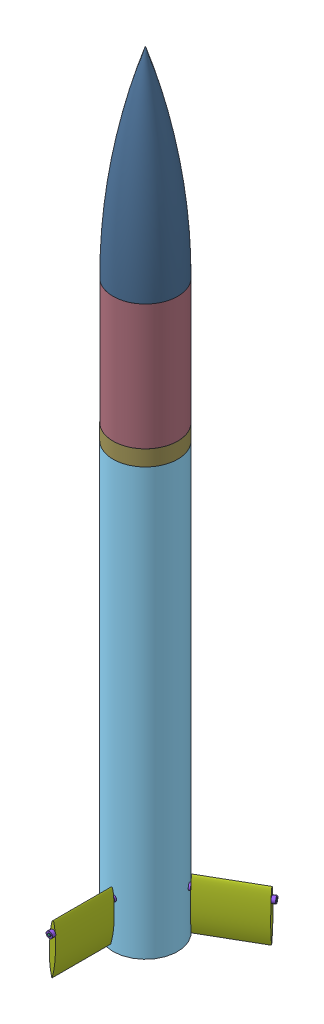
SolidWorks assembly Rocket flow study, configuration Default. Lengths in mm.
Overall size (346.59 1555.75 300.71).
35 component instances, 14 part files, 41 mates.
Components (placement in the parent):
- 57155K324_STAINLESS STEEL BALL BEARING-1: 57155K324_STAINLESS STEEL BALL BEARING [57155K324] at (60.6025 59.8698 -15.8313) x (-0.999722 -0.023582 0) z (0 0 1) size (17.53 17.53 4.98)
- 57155K324_STAINLESS STEEL BALL BEARING-2: 57155K324_STAINLESS STEEL BALL BEARING [57155K324] at (60.6025 59.8698 -3.5377) x (0.802682 0.596408 0) z (0 0 -1) size (17.53 17.53 4.98)
- three_fin_design-1: three_fin_design [Default] at (60.6025 -34.1102 -62.5321) size (127 120.65 127)
- Servo model-1: Servo model [Default] at (8.2588 8.1198 -93.0933) x (0.866025 0 0.5) z (0.5 0 -0.866025) size (29.41 54 21)
- 57155K324_STAINLESS STEEL BALL BEARING-3: 57155K324_STAINLESS STEEL BALL BEARING [57155K324] at (9.5118 59.8698 -92.0293) x (0.5 0 -0.866025) z (0.866025 0 0.5) size (17.53 17.53 4.98)
- 57155K324_STAINLESS STEEL BALL BEARING-4: 57155K324_STAINLESS STEEL BALL BEARING [57155K324] at (20.1584 59.8698 -85.8825) x (-0.5 0 0.866025) z (-0.866025 0 -0.5) size (17.53 17.53 4.98)
- 57155K324_STAINLESS STEEL BALL BEARING-5: 57155K324_STAINLESS STEEL BALL BEARING [57155K324] at (101.0466 59.8698 -85.8825) x (-0.5 0 -0.866025) z (0.866025 0 -0.5) size (17.53 17.53 4.98)
- 57155K324_STAINLESS STEEL BALL BEARING-7: 57155K324_STAINLESS STEEL BALL BEARING [57155K324] at (111.6932 59.8698 -92.0293) x (0.292704 -0.810739 0.506978) z (-0.866025 0 0.5) size (17.53 17.53 4.98)
- motor tube-2: motor tube [Default] at (60.6025 -34.1102 -62.5321) x (0.500398 0 0.865795) z (-0.865795 0 0.500398) size (58 240 58)
- Servo model-2: Servo model [Default] at (60.3075 8.1198 -1.9205) x (0 0 -1) z (-1 0 0) size (29.41 54 21)
- Servo model-3: Servo model [Default] at (113.2412 8.1198 -92.5824) x (-0.866025 0 0.5) z (0.5 0 0.866025) size (29.41 54 21)
- BodyTube(34in)-1: BodyTube(34in) [Default] at (60.6025 -34.1102 -62.5321) x (-0.070711 0 0.997497) z (-0.997497 0 -0.070711) size (130.89 863.6 130.89)
- fin_assembly-1: fin_assembly [Default] at (-45.0569 295.68 404.8684) x (0.011108 -0.999753 0.01924) z (0.866025 0 -0.5) size (102.27 14.01 158.75)
  - 8632T141_D-PROFILE SHAFT-1: 8632T141_D-PROFILE SHAFT [8632T141] at (227.9327 357.1031 441.2341) size (6.35 5.92 158.75)
  - fin-1: fin [Default] at (206.3327 357.1031 393.8313) size (102.27 12.29 119)
  - 9414T600_SET SCREW SHAFT COLLAR-1: 9414T600_SET SCREW SHAFT COLLAR [9414T6] at (227.9327 357.1031 516.4022) x (-0.10942 -0.993996 0) z (0 0 1) size (12.7 12.7 7.14)
  - 9414T600_SET SCREW SHAFT COLLAR-2: 9414T600_SET SCREW SHAFT COLLAR [9414T6] at (227.9327 357.1031 390.2594) x (-0.10942 -0.993996 0) z (0 0 1) size (12.7 12.7 7.14)
- horn-1: horn [Default] at (86.048 -3.2802 -76.8824) x (0.499417 0.048297 0.865015) z (-0.024148 0.998833 -0.041826) size (44 6 12)
- horn-2: horn [Default] at (60.3075 -3.2802 -33.3205) x (-0.998833 0.048297 0) z (0.048297 0.998833 0) size (44 6 12)
- horn-3: horn [Default] at (35.452 -3.2802 -77.3933) x (0.499417 0.048297 -0.865015) z (-0.024148 0.998833 0.041826) size (44 6 12)
- fin_assembly-2: fin_assembly [Default] at (518.2129 295.68 -204.7286) x (0.011108 -0.999753 -0.01924) z (-0.866025 0 -0.5) size (102.27 14.01 158.75)
  - 8632T141_D-PROFILE SHAFT-1: 8632T141_D-PROFILE SHAFT [8632T141] at (227.9327 357.1031 441.2341) size (6.35 5.92 158.75)
  - fin-1: fin [Default] at (206.3327 357.1031 393.8313) size (102.27 12.29 119)
  - 9414T600_SET SCREW SHAFT COLLAR-1: 9414T600_SET SCREW SHAFT COLLAR [9414T6] at (227.9327 357.1031 516.4022) x (-0.10942 -0.993996 0) z (0 0 1) size (12.7 12.7 7.14)
  - 9414T600_SET SCREW SHAFT COLLAR-2: 9414T600_SET SCREW SHAFT COLLAR [9414T6] at (227.9327 357.1031 390.2594) x (-0.10942 -0.993996 0) z (0 0 1) size (12.7 12.7 7.14)
- fin_assembly-3: fin_assembly [Default] at (-291.3485 295.68 -387.736) x (-0.022217 -0.999753 0) z (0 0 1) size (102.27 14.01 158.75)
  - 8632T141_D-PROFILE SHAFT-1: 8632T141_D-PROFILE SHAFT [8632T141] at (227.9327 357.1031 441.2341) size (6.35 5.92 158.75)
  - fin-1: fin [Default] at (206.3327 357.1031 393.8313) size (102.27 12.29 119)
  - 9414T600_SET SCREW SHAFT COLLAR-1: 9414T600_SET SCREW SHAFT COLLAR [9414T6] at (227.9327 357.1031 516.4022) x (-0.10942 -0.993996 0) z (0 0 1) size (12.7 12.7 7.14)
  - 9414T600_SET SCREW SHAFT COLLAR-2: 9414T600_SET SCREW SHAFT COLLAR [9414T6] at (227.9327 357.1031 390.2594) x (-0.10942 -0.993996 0) z (0 0 1) size (12.7 12.7 7.14)
- NoseCone-1: NoseCone [Default] at (60.6025 1521.6398 -62.5321) x (-0.99067 0 0.136279) z (0 1 0) size (130.89 130.89 508)
- Coupler(8in)-1: Coupler(8in) [Default] at (60.6025 743.1298 -62.5321) x (0.992707 0 0.120555) z (-0.120555 0 0.992707) size (127 203.2 127)
- BodyTube(1.25in)-1: BodyTube(1.25in) [Default] at (60.6025 829.4898 -62.5321) x (0.665532 0 0.746369) z (-0.746369 0 0.665532) size (130.89 31.75 130.89)
- BodyTube(10in)-1: BodyTube(10in) [Default] at (60.6025 861.2398 -62.5321) x (0.901422 0 -0.432942) z (0.432942 0 0.901422) size (130.89 254 130.89)
- CenteringCylinder-1: CenteringCylinder [Default] at (60.6025 88.4148 -62.5321) x (-0.994044 0 -0.108975) z (0.108975 0 -0.994044) size (127 114.3 127)
Mates (geometry in assembly coordinates):
- Parallel1: parallel: plane of 57155K324_STAINLESS STEEL BALL BEARING-1 through (60.7838 52.1833 -13.3421) normal (0 0 1); plane of three_fin_design-1 through (60.6025 59.8698 -14.2565) normal (0 0 -1)
- Concentric1: concentric: circle of 57155K324_STAINLESS STEEL BALL BEARING-1; circle of three_fin_design-1
- Coincident2: coincident: plane of 57155K324_STAINLESS STEEL BALL BEARING-1 through (60.7448 53.8362 -17.3045) normal (0 0 1); plane of three_fin_design-1 through (60.6025 59.8698 -17.3045) normal (0 0 -1)
- Parallel4: parallel: plane of 57155K324_STAINLESS STEEL BALL BEARING-2 through (63.6306 55.7943 -6.0269) normal (0 0 -1); plane of three_fin_design-1 through (60.6025 59.8698 -6.1285) normal (0 0 1)
- Coincident4: coincident: plane of 57155K324_STAINLESS STEEL BALL BEARING-2 through (64.2019 55.0254 -2.0645) normal (0 0 -1); plane of three_fin_design-1 through (60.6025 59.8698 -2.0645) normal (0 0 1)
- Concentric3: concentric: cylinder of 57155K324_STAINLESS STEEL BALL BEARING-2 through (60.6025 59.8698 -6.0269) axis (0 0 -1) radius 3.175; cylinder of three_fin_design-1 through (60.6025 59.8698 0.9679) axis (0 0 -1) radius 3.429
- Parallel5: parallel: plane of three_fin_design-1 through (11.7555 59.8698 -90.7339) normal (-0.866025 0 -0.5); plane of 57155K324_STAINLESS STEEL BALL BEARING-3 through (11.6675 67.5584 -90.7847) normal (0.866025 0 0.5)
- Concentric5: concentric: circle of three_fin_design-1; circle of 57155K324_STAINLESS STEEL BALL BEARING-3
- Coincident5: coincident: plane of three_fin_design-1 through (8.236 59.8698 -92.7659) normal (-0.866025 0 -0.5); plane of 57155K324_STAINLESS STEEL BALL BEARING-3 through (8.236 65.905 -92.7659) normal (0.866025 0 0.5)
- Parallel7: parallel: plane of three_fin_design-1 through (102.4104 59.8698 -86.6699) normal (-0.866025 0 0.5); plane of 57155K324_STAINLESS STEEL BALL BEARING-5 through (103.2023 67.5584 -87.1271) normal (0.866025 0 -0.5)
- Concentric7: concentric: cylinder of three_fin_design-1 through (115.5951 59.8698 -94.2821) axis (-0.866025 0 0.5) radius 3.429; cylinder of 57155K324_STAINLESS STEEL BALL BEARING-5 through (103.2023 59.8698 -87.1271) axis (0.866025 0 -0.5) radius 3.175
- Coincident6: coincident: plane of three_fin_design-1 through (99.7708 59.8698 -85.1459) normal (-0.866025 0 0.5); plane of 57155K324_STAINLESS STEEL BALL BEARING-5 through (99.7708 65.905 -85.1459) normal (0.866025 0 -0.5)
- Parallel10: parallel: plane of three_fin_design-1 through (18.7946 59.8698 -86.6699) normal (0.866025 0 0.5); plane of 57155K324_STAINLESS STEEL BALL BEARING-4 through (18.0027 67.5584 -87.1271) normal (-0.866025 0 -0.5)
- Concentric8: concentric: cylinder of three_fin_design-1 through (5.6099 59.8698 -94.2821) axis (0.866025 0 0.5) radius 3.429; cylinder of 57155K324_STAINLESS STEEL BALL BEARING-4 through (18.0027 59.8698 -87.1271) axis (-0.866025 0 -0.5) radius 3.175
- Coincident7: coincident: plane of three_fin_design-1 through (21.4342 59.8698 -85.1459) normal (0.866025 0 0.5); plane of 57155K324_STAINLESS STEEL BALL BEARING-4 through (21.4342 65.905 -85.1459) normal (-0.866025 0 -0.5)
- Parallel11: parallel: plane of three_fin_design-1 through (109.4495 59.8698 -90.7339) normal (0.866025 0 -0.5); plane of 57155K324_STAINLESS STEEL BALL BEARING-7 through (112.6542 64.3707 -85.3864) normal (-0.866025 0 0.5)
- Concentric9: concentric: cylinder of three_fin_design-1 through (115.5951 59.8698 -94.2821) axis (-0.866025 0 0.5) radius 3.429; cylinder of 57155K324_STAINLESS STEEL BALL BEARING-7 through (109.5374 59.8698 -90.7847) axis (-0.866025 0 0.5) radius 3.175
- Coincident8: coincident: plane of three_fin_design-1 through (112.969 59.8698 -92.7659) normal (0.866025 0 -0.5); plane of 57155K324_STAINLESS STEEL BALL BEARING-7 through (115.4155 63.4028 -88.5284) normal (-0.866025 0 0.5)
- Parallel12: parallel: plane of three_fin_design-1 through (6.9162 -34.1102 -93.5279) normal (0.866025 0 0.5); plane of Servo model-1 through (8.2588 8.1198 -93.0933) normal (-0.866025 0 -0.5)
- Coincident9: coincident: plane of three_fin_design-1 through (30.2516 80.1898 -98.386) normal (0.866025 0 0.5); plane of Servo model-1 through (22.4616 8.1198 -84.8933) normal (-0.866025 0 -0.5)
- Parallel13: parallel: plane of three_fin_design-1 through (1.5187 28.1198 -84.1791) normal (0.5 0 -0.866025); plane of Servo model-1 through (17.2116 -11.8802 -75.8001) normal (-0.5 0 0.866025)
- Coincident10: coincident: plane of three_fin_design-1 through (1.5187 28.1198 -84.1791) normal (0 -1 0); plane of Servo model-1 through (27.7116 28.1198 -93.9866) normal (0 1 0)
- Coincident11: coincident: plane of three_fin_design-1 through (12.3137 28.1198 -102.8766) normal (-0.5 0 0.866025); plane of Servo model-1 through (27.7116 -11.8802 -93.9866) normal (0.5 0 -0.866025)
- Concentric10: concentric: cylinder of three_fin_design-1 through (60.6025 86.5398 -62.5321) axis (0 -1 0) radius 29; cylinder of motor tube-2 through (60.6025 205.8898 -62.5321) axis (0 -1 0) radius 29
- Coincident12: coincident: plane of three_fin_design-1 through (60.6025 -34.1102 -62.5321) normal (0 -1 0); plane of motor tube-2 through (60.6025 -34.1102 -62.5321) normal (0 -1 0)
- Concentric11: concentric: cylinder of 57155K324_STAINLESS STEEL BALL BEARING-7 through (109.5374 59.8698 -90.7847) axis (-0.866025 0 0.5) radius 3.175; cylinder of fin_assembly-1/8632T141_D-PROFILE SHAFT-1 through (229.8283 59.8698 -160.2346) axis (-0.866025 0 0.5) radius 3.175
- Coincident13: coincident: plane of 57155K324_STAINLESS STEEL BALL BEARING-7 through (115.2368 61.8742 -90.8699) normal (0.866025 0 -0.5); plane of fin_assembly-1/9414T600_SET SCREW SHAFT COLLAR-2 through (113.8489 59.8698 -93.2739) normal (-0.866025 0 0.5)
- Concentric13: concentric: cylinder of Servo model-3 through (91.2909 -3.2802 -79.9094) axis (-0.866025 0 0.5) radius 2.9983; cylinder of horn-1 through (87.7714 -3.2802 -77.8774) axis (0.866025 0 -0.5) radius 2.5
- Coincident15: coincident: plane of Servo model-3 through (91.2441 8.1198 -79.8824) normal (-0.866025 0 0.5); plane of horn-1 through (91.2441 -3.2802 -79.8824) normal (0.866025 0 -0.5)
- Concentric14: concentric: cylinder of three_fin_design-1 through (60.6025 -21.4102 -62.5321) axis (0 -1 0) radius 63.5; cylinder of BodyTube(34in)-1 through (60.6025 829.4898 -62.5321) axis (0 -1 0) radius 63.5
- Concentric15: concentric: cylinder of Coupler(8in)-1 through (60.6025 946.3298 -62.5321) axis (0 -1 0) radius 63.5; cylinder of BodyTube(1.25in)-1 through (60.6025 861.2398 -62.5321) axis (0 -1 0) radius 63.5
- Concentric16: concentric: cylinder of BodyTube(34in)-1 through (60.6025 829.4898 -62.5321) axis (0 -1 0) radius 63.5; cylinder of Coupler(8in)-1 through (60.6025 946.3298 -62.5321) axis (0 -1 0) radius 63.5
- Concentric17: concentric: cylinder of Coupler(8in)-1 through (60.6025 946.3298 -62.5321) axis (0 -1 0) radius 63.5; cylinder of BodyTube(10in)-1 through (60.6025 1115.2398 -62.5321) axis (0 -1 0) radius 63.5
- Concentric18: concentric: cylinder of NoseCone-1 through (60.6025 1013.6398 -62.5321) axis (0 1 0) radius 63.5; cylinder of BodyTube(10in)-1 through (60.6025 1115.2398 -62.5321) axis (0 -1 0) radius 63.5
- Concentric19: concentric: cylinder of motor tube-2 through (60.6025 205.8898 -62.5321) axis (0 -1 0) radius 29; cylinder of CenteringCylinder-1 through (60.6025 202.7148 -62.5321) axis (0 -1 0) radius 28.9941
- Distance1: distance = 85.09 mm: plane of BodyTube(1.25in)-1 through (60.6025 861.2398 -62.5321) normal (0 1 0); plane of Coupler(8in)-1 through (60.6025 946.3298 -62.5321) normal (0 1 0)
- Distance2: distance = 3.175 mm: plane of CenteringCylinder-1 through (60.6025 202.7148 -62.5321) normal (0 1 0); plane of motor tube-2 through (60.6025 205.8898 -62.5321) normal (0 1 0)
- Coincident17: coincident: plane of BodyTube(1.25in)-1 through (60.6025 861.2398 -62.5321) normal (0 1 0); plane of BodyTube(10in)-1 through (60.6025 861.2398 -62.5321) normal (0 -1 0)
- Coincident18: coincident: plane of BodyTube(34in)-1 through (60.6025 829.4898 -62.5321) normal (0 1 0); plane of BodyTube(1.25in)-1 through (60.6025 829.4898 -62.5321) normal (0 -1 0)
- Coincident19: coincident: plane of NoseCone-1 through (60.6025 1115.2398 -62.5321) normal (0 -1 0); plane of BodyTube(10in)-1 through (60.6025 1115.2398 -62.5321) normal (0 1 0)
- Coincident20: coincident: plane of three_fin_design-1 through (60.6025 -34.1102 -62.5321) normal (0 -1 0); plane of BodyTube(34in)-1 through (60.6025 -34.1102 -62.5321) normal (0 -1 0)
